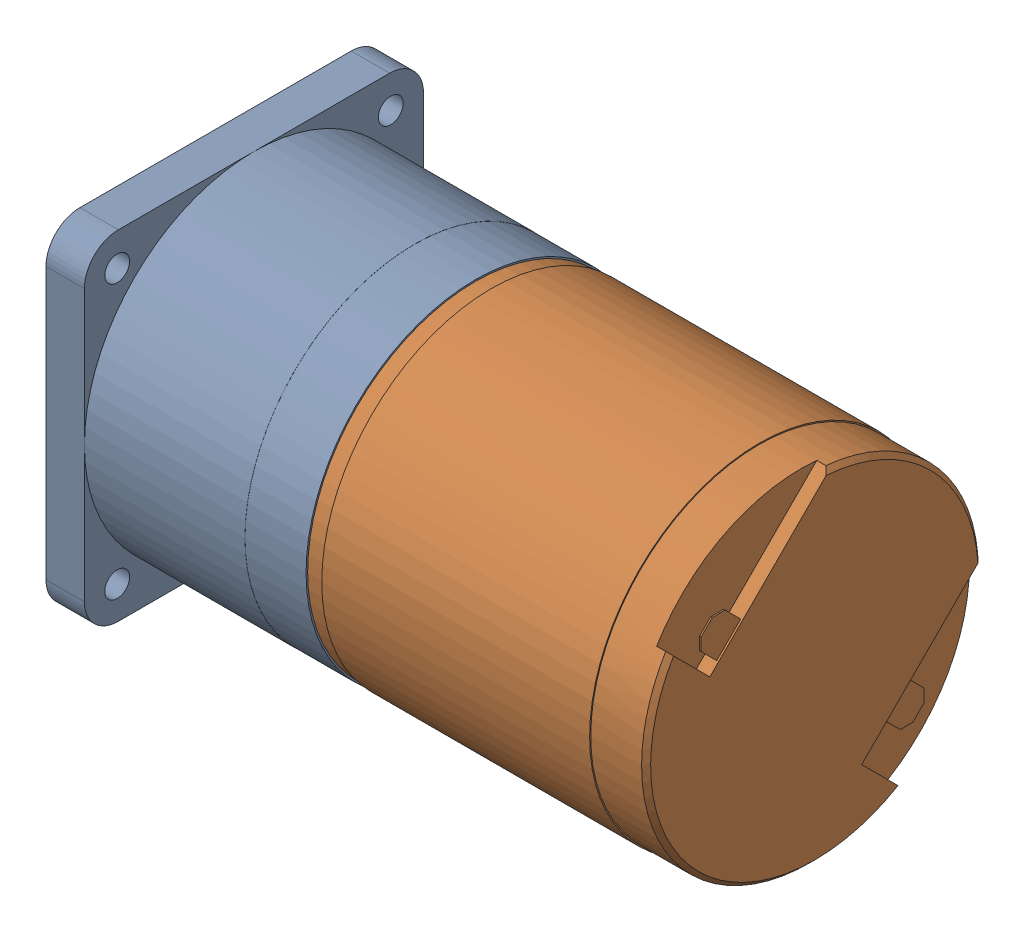
SolidWorks assembly Moto-reducteur, configuration Défaut. Lengths in mm.
Overall size (58.95 30 30).
2 component instances, 2 part files, 3 mates.
Components (placement in the parent):
- Reducteur GS30-1: Reducteur GS30 [Défaut] at (5.0508 1.4306 0) size (28.95 30 30)
- Moteur F2130-1: Moteur F2130 [Défaut] at (35.0508 1.4306 0) size (40.2 30 30)
Mates (geometry in assembly coordinates):
- Coïncidente1: coincident anti-aligned: plane of Reducteur GS30-1 through (5.0508 1.4306 0) normal (1 0 0); plane of Moteur F2130-1 through (5.0508 16.2806 0) normal (-1 0 0)
- Coaxiale1: concentric aligned: circle of Reducteur GS30-1; circle of Moteur F2130-1
- Angle1: planar angle = 3.926991 rad anti-aligned: plane of Reducteur GS30-1 through (-17.9492 16.4306 15) normal (0 0 1); plane of Moteur F2130-1 through (33.8508 24.6088 -9.7432) normal (0 0.707107 0.707107)
